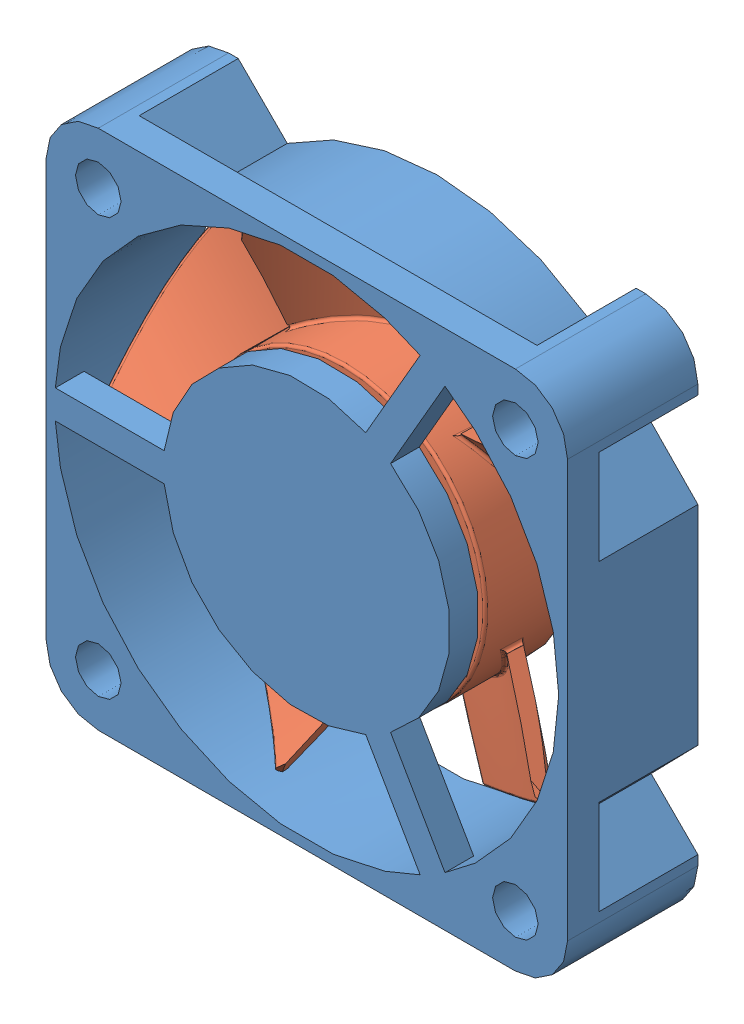
SolidWorks assembly 40 x 40 x 10 Fan assembly, configuration Default. Lengths in mm.
Overall size (43.51 43.41 10.23).
2 component instances, 2 part files, 7 mates.
Components (placement in the parent):
- 40 x 40 x 10 Fan Case-1: 40 x 40 x 10 Fan Case [Default] x (-1 0 0) z (0 0 -1) size (40 40 10)
- 40 x 40 x 10 Fan Rotor-1: 40 x 40 x 10 Fan Rotor [Default] at (0 0 -4.7) x (0.992079 0.125613 0) z (0.125613 -0.992079 0) size (38.94 9.45 38.83)
Mates (geometry in assembly coordinates):
- Coincident1: coincident aligned: plane of 40 x 40 x 10 Fan Case-1; plane of assembly through (0 0 0) normal (0 1 0)
- Coincident2: coincident anti-aligned: plane of 40 x 40 x 10 Fan Case-1 through (0 0 0) normal (0 0 -1); plane of assembly through (0 0 0) normal (0 0 1)
- Coincident3: coincident: point of 40 x 40 x 10 Fan Case-1; plane of assembly
- Concentric1: concentric: cylinder of 40 x 40 x 10 Fan Case-1 through (0 0 5) axis (0 0 -1) radius 19.325; cylinder of ? through (0 0 -3.1) axis (0 0 1) radius 10.9
- Distance1: distance = 0.1 mm: plane of ? through (0 0 -3.1) normal (0 0 -1); plane of 40 x 40 x 10 Fan Case-1 through (0 0 2.8) normal (0 0 -1)
- Concentric2: concentric aligned: cylinder of 40 x 40 x 10 Fan Case-1 through (0 0 5) axis (0 0 -1) radius 19.325; cylinder of 40 x 40 x 10 Fan Rotor-1 through (0 0 2.3) axis (0 0 -1) radius 11
- Distance2: distance = 0.5 mm anti-aligned: plane of 40 x 40 x 10 Fan Rotor-1 through (0 0 2.3) normal (0 0 1); plane of 40 x 40 x 10 Fan Case-1 through (0 0 2.8) normal (0 0 -1)
